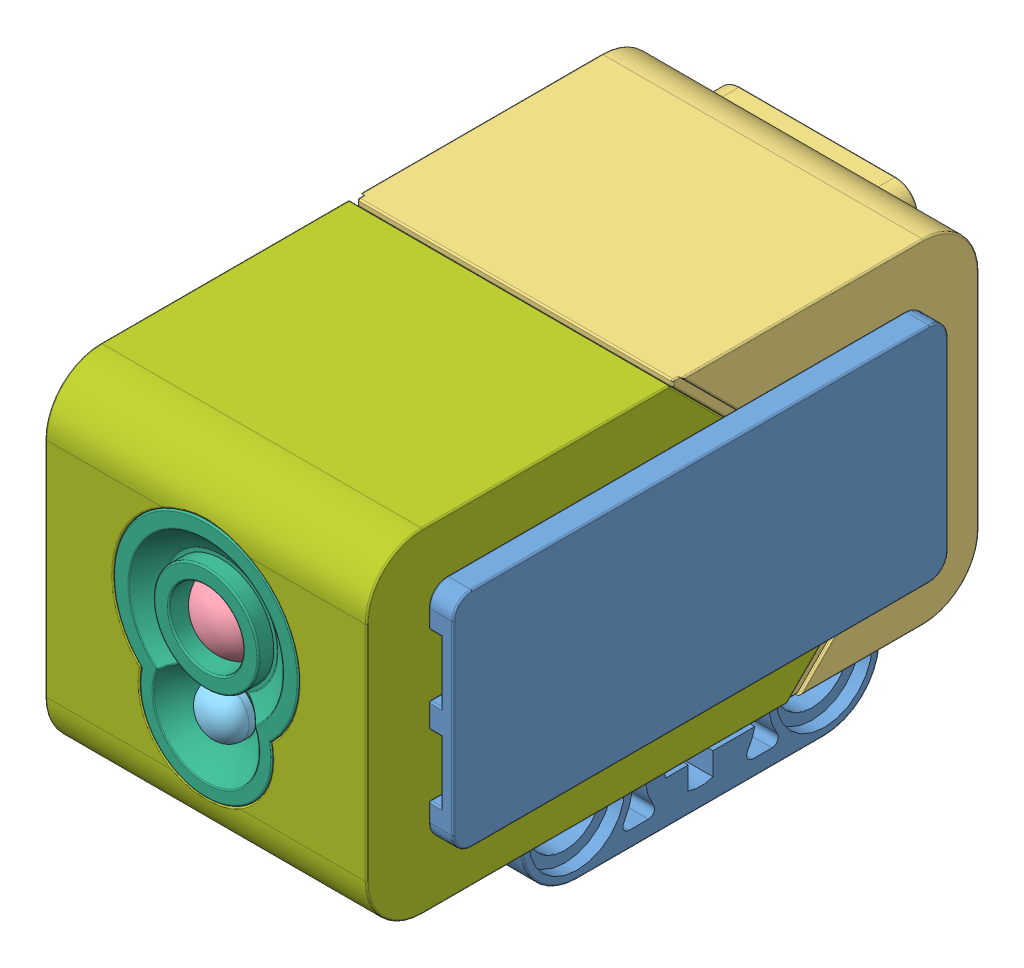
SolidWorks assembly EV3 Color Sensor , configuration Default. Lengths in mm.
Overall size (24 31.04 39.66).
8 component instances, 7 part files, 0 mates.
Components (placement in the parent):
- 95650.stp-1: 95650.stp [Default] at origin size (24 31.04 39.66)
  - 99377-LtBluishGray.stp-1: 99377-LtBluishGray.stp [Default] at origin size (24 29.6 38)
  - 54732b-LtBluishGray.stp-1: 54732b-LtBluishGray.stp [Default] at (0 2.04 -20.2) x (-1 0 0) z (0 0 -1) size (12 14.56 14.4)
  - 99376-White.stp-1: 99376-White.stp [Default] at (0 0.44 -14.2) size (22.3 23.6 19.62)
  - 11013-TransClear.stp-1: 11013-TransClear.stp [Default] at (0 2.24 17.4) x (1 0 0) z (0 -1 0) size (4.8 7.2 4.8)
  - 99396-TransClear.stp-1: 99396-TransClear.stp [Default] at (0 -2.96 18.2) x (1 0 0) z (0 -1 0) size (3.2 5.6 3.2)
  - 11014p01-Black.stp-1: 11014p01-Black.stp [Default] at (0 2.24 19.4) size (12 15.5 9.2)
  - 99388-LtBluishGray.stp-1: 99388-LtBluishGray.stp [Default] at (0 0.44 13.8) size (22.4 21.6 30.69)
